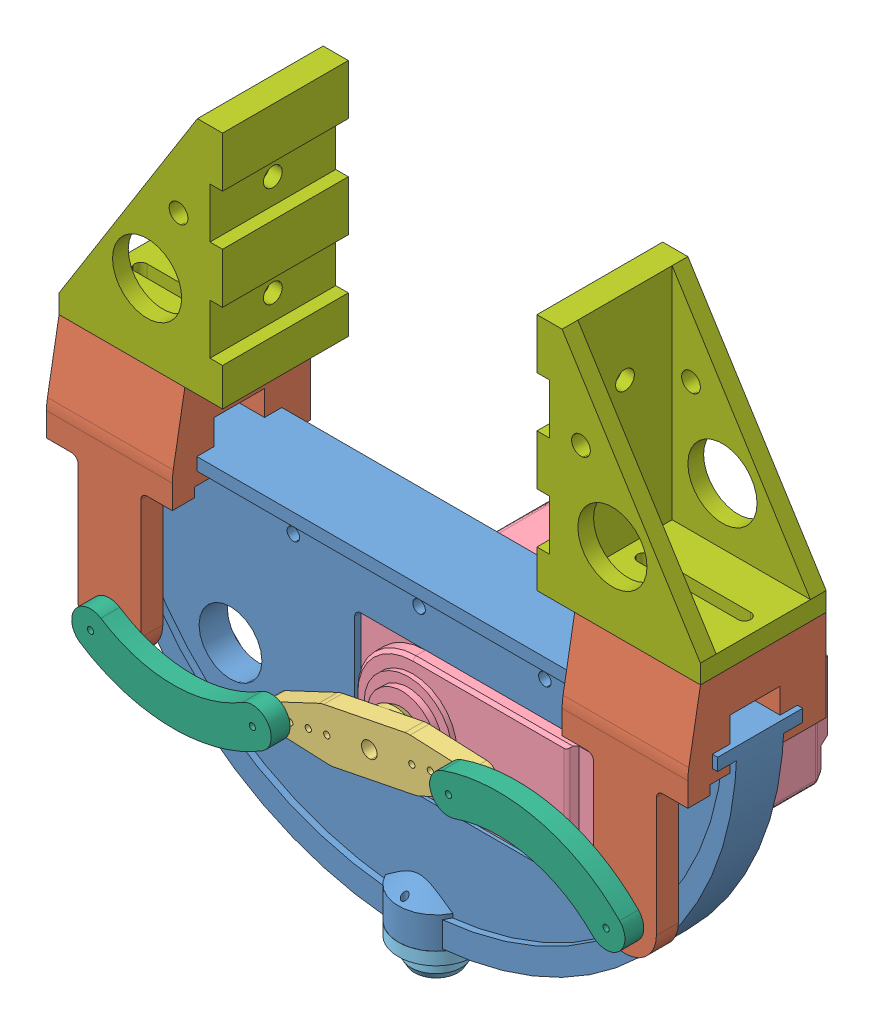
SolidWorks assembly gripper, configuration Default. Lengths in mm.
Overall size (103 105.59 46.92).
10 component instances, 7 part files, 26 mates.
Components (placement in the parent):
- Base-2: Base [Default] at (33.7191 77.8867 75.9336) x (-1 0 0) z (0 0 1) size (103 51.59 13.5)
- Part3 (2)-1: Part3 (2) [Default] at (-17.6178 88.3867 93.3536) x (0 0 -1) z (1 0 0) size (22 41 20)
- Part3 (2)-2: Part3 (2) [Default] at (64.3822 88.3867 93.3536) x (0 0 -1) z (1 0 0) size (22 41 20)
- Estrella-1: Estrella [Predeterminado] at (33.7191 55.1367 93.3536) x (0.195763 -0.980651 0) z (0.980651 0.195763 0) size (8 5 35.3)
- Servo MG966R-1: Servo MG966R [Predeterminado] at (43.8191 55.1367 66.9336) x (-1 0 0) z (0 1 0) size (54.7 41.75 20.5)
- holder-1: holder [Default] at (33.7191 24.2967 82.7263) x (1 0 0) z (0 -1 0) size (12 12 5.5)
- Part4-1: Part4 [Default] at (7.4029 52.9895 93.3536) x (-0.999999 -0.001249 0) z (0 0 1) size (31.74 9.94 3)
- Part4-2: Part4 [Default] at (59.5804 55.0116 93.3536) x (0.977109 -0.21274 0) z (0 0 1) size (31.74 9.94 3)
- Part2-2: Part2 [Default] at (-4.6178 88.3867 71.3536) size (26 38 20)
- Part2-3: Part2 [Default] at (71.3822 88.3867 91.3536) x (-1 0 0) z (0 0 -1) size (26 38 20)
Mates (geometry in assembly coordinates):
- Coincident1: coincident anti-aligned: plane of Base-2 through (85.2191 77.8867 89.4336) normal (0 1 0); plane of Part3 (2)-1 through (-38.4144 77.8867 89.4336) normal (0 -1 0)
- Coincident2: coincident anti-aligned: plane of Base-2 through (33.7191 77.8867 89.4336) normal (0 0 1); plane of Part3 (2)-1 through (-38.4144 75.8867 89.4336) normal (0 0 -1)
- Coincident4: coincident anti-aligned: plane of Base-2 through (33.7191 77.8867 75.9336) normal (0 0 -1); plane of Part3 (2)-2 through (43.5856 77.8867 75.9336) normal (0 0 1)
- Coincident5: coincident anti-aligned: plane of Base-2 through (85.2191 77.8867 89.4336) normal (0 1 0); plane of Part3 (2)-2 through (43.5856 77.8867 89.4336) normal (0 -1 0)
- Coincident12: coincident aligned: plane of Part3 (2)-1 through (2.3822 88.3867 93.3536) normal (0 0 1); plane of Estrella-1 through (33.7191 55.1367 93.3536) normal (0 0 1)
- Coincident14: coincident anti-aligned: plane of Base-2 through (24.4691 44.8867 131.0049) normal (0 1 0); plane of Servo MG966R-1 through (43.8191 44.8867 66.9336) normal (0 -1 0)
- Concentric2: concentric aligned: cone of Estrella-1 through (33.7191 55.1367 88.3536) axis (0 0 -1); cylinder of Servo MG966R-1 through (33.7191 55.1367 91.1836) axis (0 0 -1) radius 3
- Coincident15: coincident anti-aligned: plane of Base-2 through (64.1691 45.8867 131.0049) normal (-1 0 0); plane of Servo MG966R-1 through (64.1691 65.3867 49.4336) normal (1 0 0)
- Coincident17: coincident: plane of Base-2 through (33.7191 79.8867 80.9336) normal (0 0 -1); line of Servo MG966R-1 through (64.1691 55.6367 80.9336) axis (0 -1 0)
- Parallel2: parallel aligned: plane of Base-2 through (33.7191 79.8867 85.4336) normal (0 0 1); plane of Servo MG966R-1 through (64.1691 65.3867 84.4336) normal (0 0 1)
- Coincident18: coincident anti-aligned: plane of Base-2 through (33.7191 26.2967 82.7263) normal (0 -1 0); plane of holder-1 through (33.7191 26.2967 82.7263) normal (0 1 0)
- Concentric3: concentric aligned: cylinder of Base-2 through (33.7191 34.2967 87.7263) axis (0 -1 0) radius 0.5; cylinder of holder-1 through (33.7191 27.7109 87.7263) axis (0 -1 0) radius 0.5
- Concentric4: concentric aligned: cylinder of Base-2 through (33.7191 34.2967 77.7263) axis (0 -1 0) radius 0.5; cylinder of holder-1 through (33.7191 27.7109 77.7263) axis (0 -1 0) radius 0.5
- Concentric5: concentric aligned: circle of Part3 (2)-1; circle of Part4-1
- Concentric6: concentric anti-aligned: circle of Estrella-1; circle of Part4-1
- Coincident21: coincident anti-aligned: plane of Part3 (2)-1 through (2.3822 88.3867 93.3536) normal (0 0 1); plane of Part4-1 through (-1.0387 62.4401 93.3536) normal (0 0 -1)
- Coincident24: coincident anti-aligned: plane of Part3 (2)-2 through (84.3822 88.3867 93.3536) normal (0 0 1); plane of Part4-2 through (65.8045 43.9737 93.3536) normal (0 0 -1)
- Concentric9: concentric anti-aligned: cylinder of Estrella-1 through (49.3111 58.2492 90.3536) axis (0 0 1) radius 0.5; cylinder of Part4-2 through (49.3111 58.2492 96.3536) axis (0 0 -1) radius 0.5
- Concentric10: concentric anti-aligned: cylinder of Part3 (2)-2 through (74.3822 52.3867 88.4394) axis (0 0 1) radius 0.5; cylinder of Part4-2 through (74.3822 52.3867 96.3536) axis (0 0 -1) radius 0.5
- Coincident25: coincident anti-aligned: plane of Part3 (2)-1 through (2.3822 88.3867 93.3536) normal (0 1 0); plane of Part2-2 through (-17.6178 88.3867 91.3536) normal (0 -1 0)
- Coincident27: coincident aligned: plane of Part3 (2)-1 through (2.3822 88.3867 71.3536) normal (0 0 -1); plane of Part2-2 through (-4.6178 88.3867 71.3536) normal (0 0 -1)
- Coincident28: coincident aligned: plane of Part3 (2)-1 through (-17.6178 88.3867 93.3536) normal (-1 0 0); plane of Part2-2 through (-17.6178 88.3867 91.3536) normal (-1 0 0)
- Coincident29: coincident anti-aligned: plane of Part3 (2)-2 through (84.3822 88.3867 93.3536) normal (0 1 0); plane of Part2-3 through (84.3822 88.3867 71.3536) normal (0 -1 0)
- Coincident30: coincident aligned: plane of Part3 (2)-2 through (84.3822 88.3867 71.3536) normal (0 0 -1); plane of Part2-3 through (71.3822 88.3867 71.3536) normal (0 0 -1)
- Coincident31: coincident aligned: plane of Part3 (2)-2 through (84.3822 88.3867 93.3536) normal (1 0 0); plane of Part2-3 through (84.3822 88.3867 71.3536) normal (1 0 0)
- LimitDistance1: limit distance = 50 mm anti-aligned: plane of Part2-2 through (8.3822 88.3867 91.3536) normal (1 0 0); plane of Part2-3 through (58.3822 88.3867 71.3536) normal (-1 0 0)
